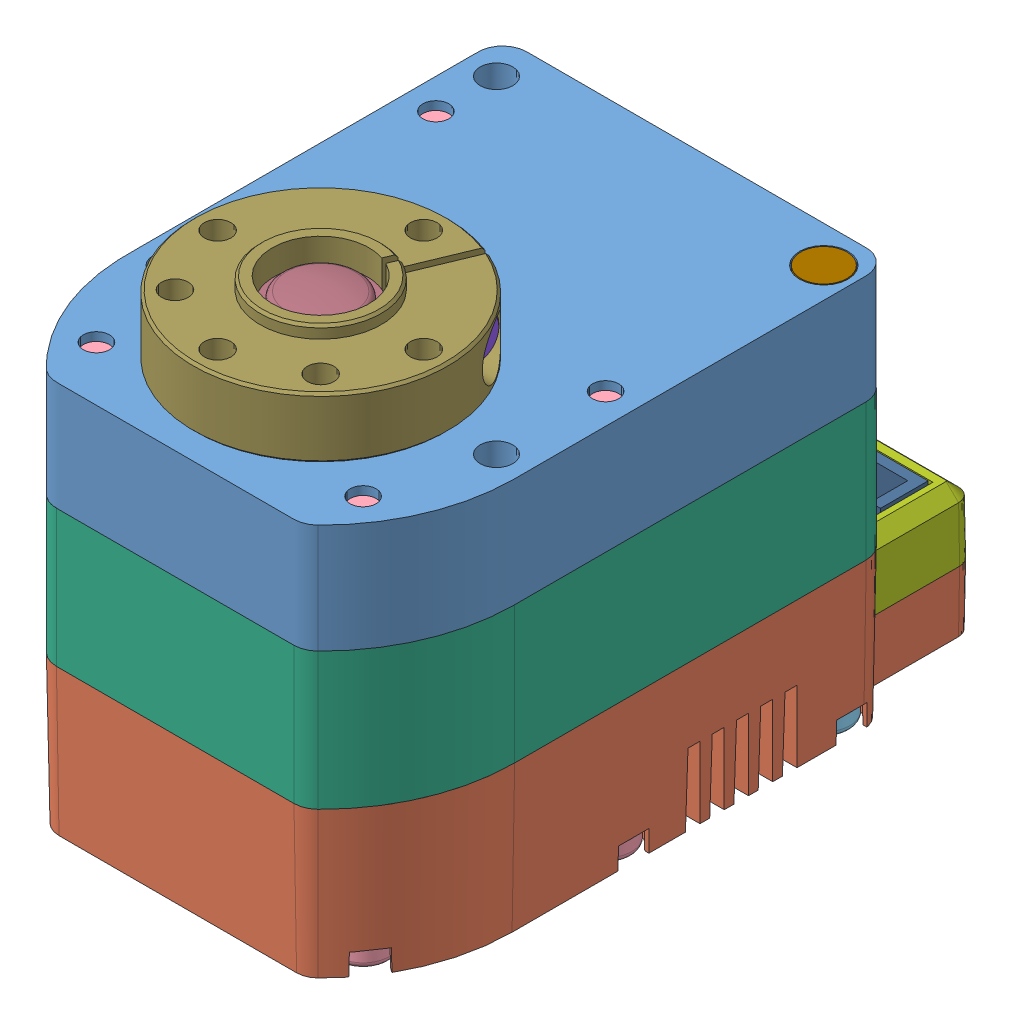
SolidWorks assembly kondo_servo_motor, configuration ﾃﾞﾌｫﾙﾄ. Lengths in mm.
Overall size (36.43 44.5 53.48).
21 component instances, 15 part files, 0 mates.
Components (placement in the parent):
- 60K-アッパーケース-1: 60K-アッパーケース [ﾃﾞﾌｫﾙﾄ] at (0 21.5195 0) x (0.000004 0 1) z (0 1 0) size (47.43 36.43 9)
- 60K-ボトムケースASSY-1: 60K-ボトムケースASSY [ﾃﾞﾌｫﾙﾄ] at (0 -4.4805 0) size (32 18.6 51.5)
  - 60K-ボトムケース-1: 60K-ボトムケース [ﾃﾞﾌｫﾙﾄ] at (0 5.7 0) size (32 18.6 51.5)
  - 60K-インサートナット_L=7mm-1: 60K-インサートナット_L=7mm [ﾃﾞﾌｫﾙﾄ] at (0 -5 0) x (-0.600327 0 -0.799755) z (-0.799755 0 0.600327) size (4.5 7 4.5)
- 60K-M2.6ナベビス_30mm-1: 60K-M2.6ナベビス_30mm [ﾃﾞﾌｫﾙﾄ] at (-13.5 -9.1805 -23) x (-0.779621 0 -0.626252) z (-0.626252 0 0.779621) size (4.3 31.8 4.3)
- 60K-M2.6ナベビス_16mm-1: 60K-M2.6ナベビス_16mm [ﾃﾞﾌｫﾙﾄ] at (13.5 -9.1805 -28) x (0.562985 0 -0.826467) z (-0.826467 0 -0.562985) size (4.3 17.8 4.3)
- 60K-ミドルケース-1: 60K-ミドルケース [ﾃﾞﾌｫﾙﾄ] at (-0.0001 21.5195 0) x (0.000001 0 1) z (0 1 0) size (43 32 13.3)
- 60K-コネクターカバー-1: 60K-コネクターカバー [ﾃﾞﾌｫﾙﾄ] at (0 -4.6805 -31) x (-1 0 0) z (0 0 -1) size (28.8 8.2 10)
- 60K-M2キャップビス_12mm-1: 60K-M2キャップビス_12mm [ﾃﾞﾌｫﾙﾄ] at (5.5 24.5195 -5.5) x (0 0 -1) z (1 0 0) size (3.8 3.8 14)
- 60K-M2.6サラビス（小頭）_13mm-1: 60K-M2.6サラビス（小頭）_13mm [ﾃﾞﾌｫﾙﾄ] at (13.5 20.3195 -28) x (0.442341 0 -0.896847) z (0.896847 0 0.442341) size (3.8 13 3.8)
- 60K-メイン基板ASSY-1: 60K-メイン基板ASSY [ﾃﾞﾌｫﾙﾄ] at (-0.0001 21.5195 0.0002) size (28.4 10.4 48.3)
  - B4B-XH-A-1: B4B-XH-A [ﾃﾞﾌｫﾙﾄ] at (-6.2999 -27.7 -34.725) size (12.4 10.4 5.75)
  - 60K-メイン基板-1: 60K-メイン基板 [ﾃﾞﾌｫﾙﾄ] at (0.0001 -28.9 0) x (-1 0 0) z (0 0 -1) size (28.4 2.7 48.3)
  - B4B-XH-A-2: B4B-XH-A [ﾃﾞﾌｫﾙﾄ] at (6.3001 -27.7 -34.725) size (12.4 10.4 5.75)
- 60K-M2.6ナベビス_30mm-2: 60K-M2.6ナベビス_30mm [ﾃﾞﾌｫﾙﾄ] at (13.5 -9.1805 -10.0024) x (0.886802 0 -0.46215) z (-0.46215 0 -0.886802) size (4.3 31.8 4.3)
- 60K-サーボホーン-1: 60K-サーボホーン [ﾃﾞﾌｫﾙﾄ] at (0 22.0195 0) size (21 7.3 21)
- 60K-M2.6ナベビス_30mm-3: 60K-M2.6ナベビス_30mm [ﾃﾞﾌｫﾙﾄ] at (-11 -9.1805 7.5) x (-0.837169 0 -0.546944) z (-0.546944 0 0.837169) size (4.3 31.8 4.3)
- 60K-M3ホーン止めビス_8mm-1: 60K-M3ホーン止めビス_8mm [ﾃﾞﾌｫﾙﾄ] at (0 25.2195 0.0002) x (0.991837 0 -0.127512) z (0.127512 0 0.991837) size (7.7 10 7.7)
- 60K-フランジベアリング_Φ8×Φ12×3.5-1: 60K-フランジベアリング_Φ8×Φ12×3.5 [ﾃﾞﾌｫﾙﾄ] at (0 20.6695 0) size (13.7 3.5 13.7)
- 60K-ギヤ-final_マグネット直付け案-1: 60K-ギヤ-final_マグネット直付け案 [ﾃﾞﾌｫﾙﾄ] at (0 14.4695 0.0002) x (1 0 0) z (0 -1 0) size (21.15 21.14 27.7)
- 60K-M2.6ナベビス_30mm-4: 60K-M2.6ナベビス_30mm [ﾃﾞﾌｫﾙﾄ] at (11 -9.1805 7.5) x (-0.837169 0 -0.546944) z (-0.546944 0 0.837169) size (4.3 31.8 4.3)
